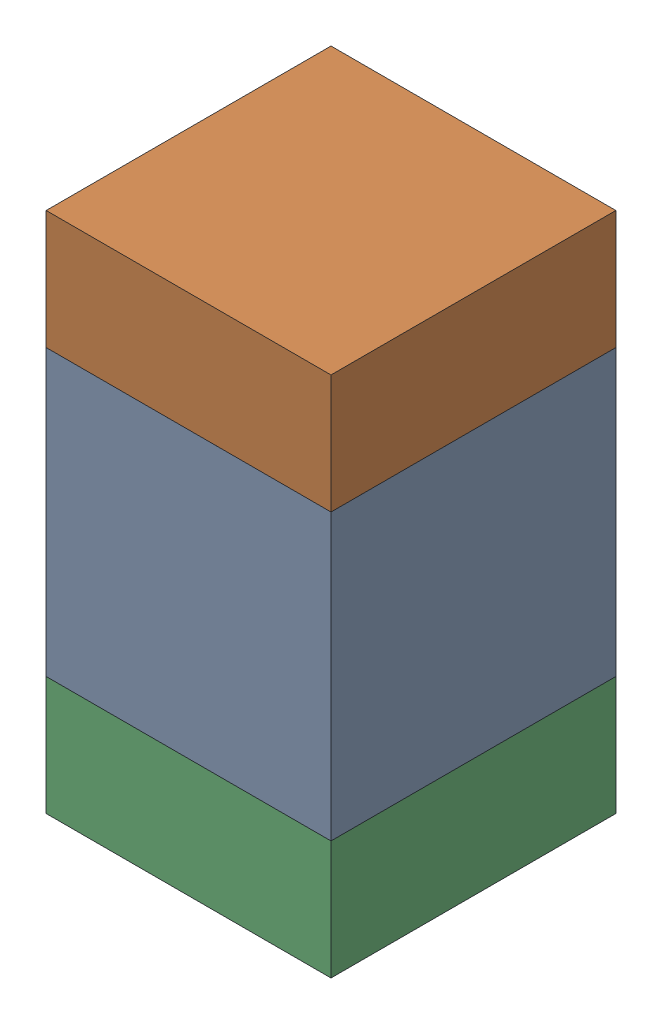
SolidWorks assembly C109_1PCB, configuration Default. Lengths in mm.
Overall size (0.6 1.1 0.6).
6 component instances, 2 part files, 0 mates.
Components (placement in the parent):
- 761606048-1: 761606048 [Default] at (116.7 111.8 0) size (0.6 0.6 0.6)
  - Extruded_9-1: Extruded_9 [Default] at origin size (0.6 0.6 0.6)
- 854785296-1: 854785296 [Default] at (116.7 112.225 0) size (0.6 0.25 0.6)
  - Extruded_10-1: Extruded_10 [Default] at origin size (0.6 0.25 0.6)
- 854785296-2: 854785296 [Default] at (116.7 111.375 0) size (0.6 0.25 0.6)
  - Extruded_10-1: Extruded_10 [Default] at origin size (0.6 0.25 0.6)
